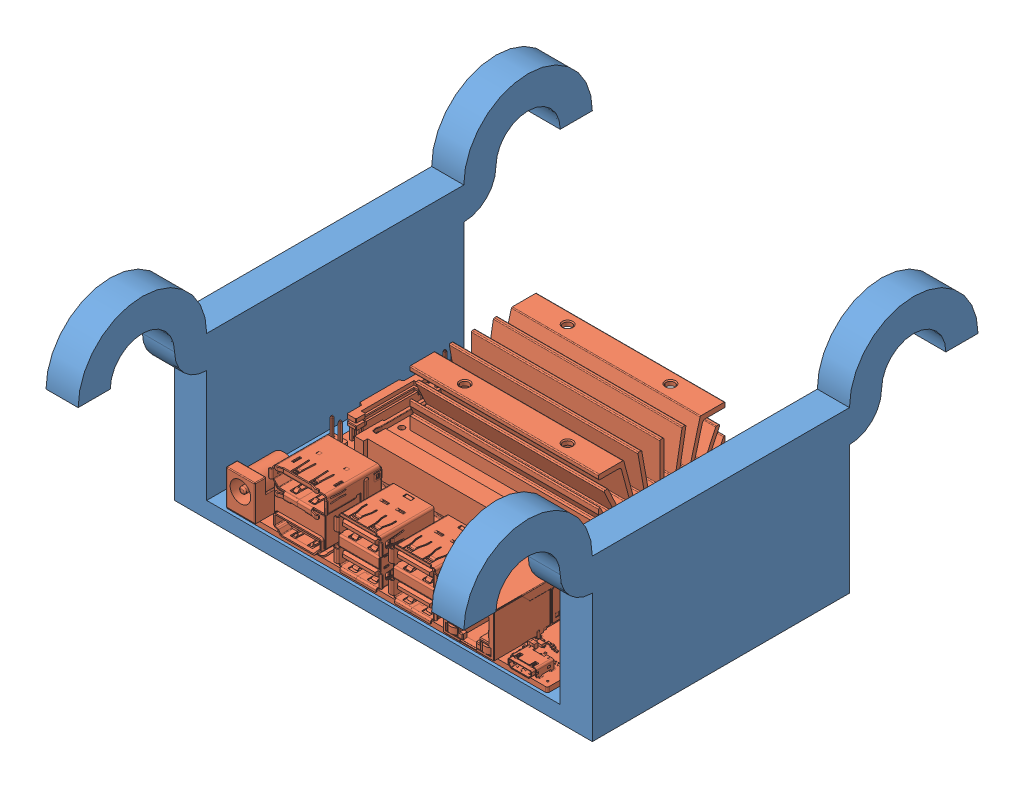
SolidWorks assembly jetson nao attachment, configuration Default. Lengths in mm.
Overall size (130 70 160).
2 component instances, 2 part files, 3 mates.
Components (placement in the parent):
- jetson nano holder-1: jetson nano holder [Default] at (39.0457 48.4865 100.9531) size (130 70 160)
- jetson nano-1: jetson nano [Default] at (-6.9543 53.4865 122.9531) x (1 0 0) z (0 1 0) size (100 81.03 30.51)
Mates (geometry in assembly coordinates):
- Coincident1: coincident: plane of jetson nano holder-1 through (-25.9543 53.4865 60.9531) normal (0 0 -1); plane of jetson nano-1 through (88.4457 53.4865 60.9531) normal (0 0 -1)
- Width1: width: plane of jetson nano holder-1 through (-15.9543 98.4865 140.9531) normal (1 0 0); plane of jetson nano holder-1 through (94.0457 98.4865 60.9531) normal (-1 0 0); plane of jetson nano-1 through (-10.9543 53.4865 61.5531) normal (-1 0 0); plane of jetson nano-1 through (89.0457 53.4865 139.3531) normal (1 0 0)
- Coincident3: coincident: plane of jetson nano holder-1 through (39.0457 53.4865 100.9531) normal (0 1 0); plane of jetson nano-1 through (-6.9543 53.4865 122.9531) normal (0 -1 0)
